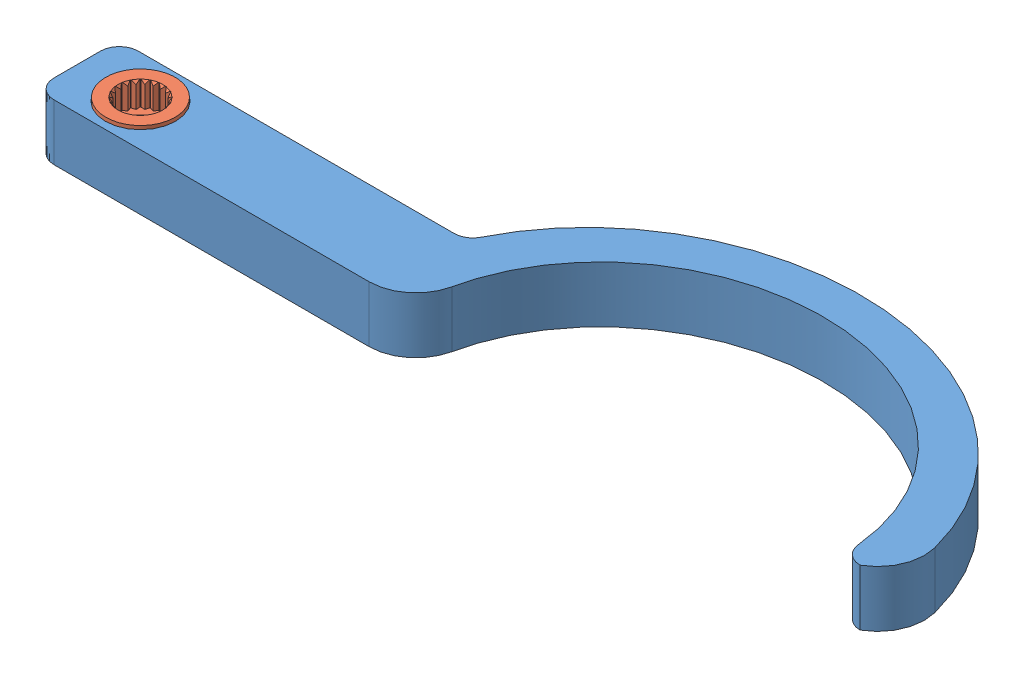
SolidWorks assembly RightClaw, configuration 默认. Lengths in mm.
Overall size (90.57 6.35 25).
2 component instances, 2 part files, 3 mates.
Components (placement in the parent):
- clawR1-1: clawR1 [默认] at (-39.7396 3.5423 98.569) size (90.57 6 25)
- MG90_Arm-1: MG90_Arm [默认] at (-39.7396 -0.2077 98.569) x (0 0 1) z (-1 0 0) size (7.4 4.1 20.9)
Mates (geometry in assembly coordinates):
- 同心1: concentric anti-aligned: cylinder of clawR1-1 through (-39.7396 -2.4577 98.569) axis (0 1 0) radius 3.75; cylinder of MG90_Arm-1 through (-39.7396 1.2923 98.569) axis (0 -1 0) radius 1.375
- 重合1: coincident anti-aligned: plane of clawR1-1 through (-39.7396 1.5423 98.569) normal (0 -1 0); plane of MG90_Arm-1 through (-32.9896 1.5423 98.569) normal (0 1 0)
- 平行1: parallel aligned: line of clawR1-1 through (-39.7396 3.5423 98.569) axis (1 0 0); line of MG90_Arm-1 through (-39.7396 -0.2077 98.569) axis (1 0 0)
